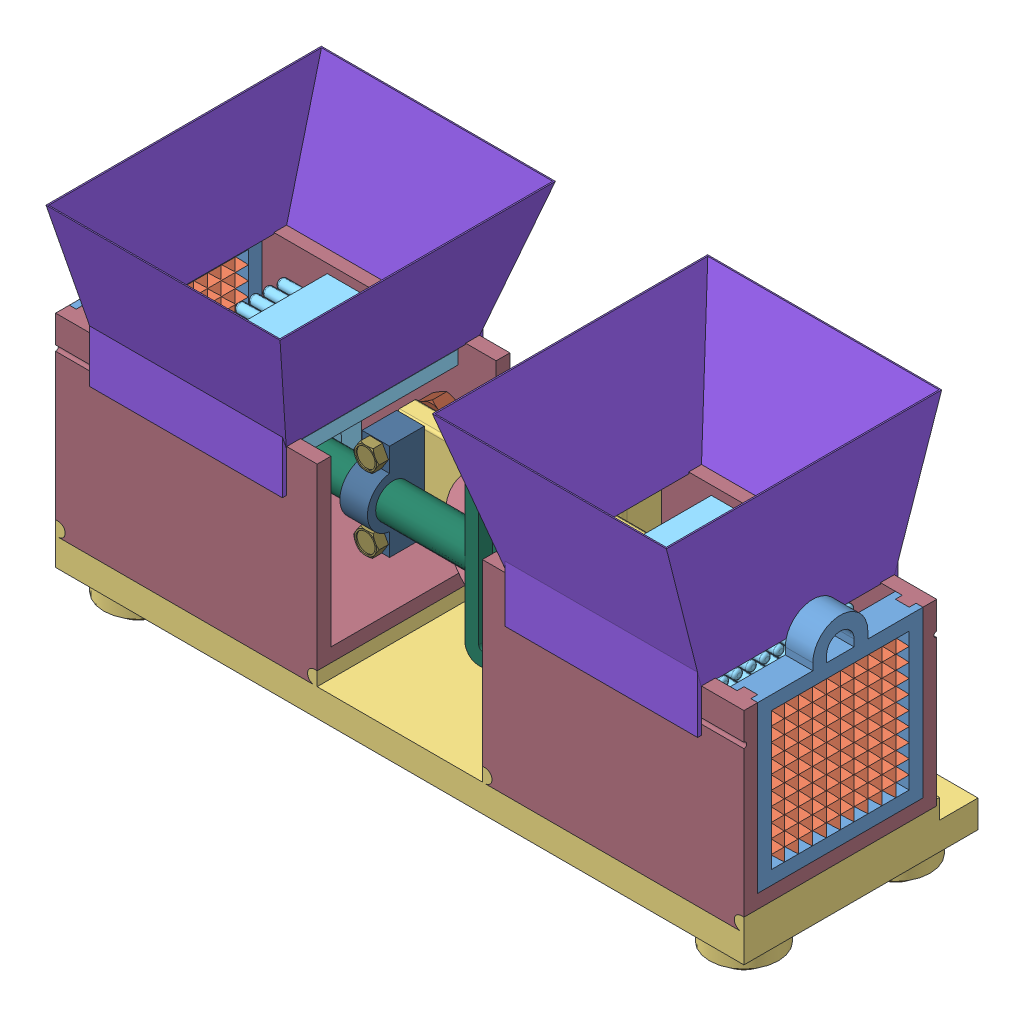
SolidWorks assembly Complete_Assmbly, configuration Default. Lengths in mm.
Overall size (546.96 281.51 365.78).
67 component instances, 15 part files, 59 mates.
Components (placement in the parent):
- Blade_assembly-1-1: Blade_assembly-1 [Default] at (92.6689 490.576 -340.9557) x (-0.150148 0.051592 0.987316) z (-0.987939 0.030407 -0.151832) size (128.96 151.07 42.39)
  - Blade Frame-1-1: Blade Frame-1 [Default] at (771.0253 -161.3106 -497.9575) x (-0.987316 0.046404 0.151832) z (-0.150148 0.037854 -0.987939) size (120 145 20)
  - Blade Piece-1-1: Blade Piece-1 [Default] at (675.3634 -97.277 -480.9651) x (0.051592 0.998205 0.030407) z (-0.150148 0.037854 -0.987939) size (1 100 20)
  - Blade Piece-1-2: Blade Piece-1 [Default] at (674.8423 -107.3589 -481.2722) x (0.051592 0.998205 0.030407) z (-0.150148 0.037854 -0.987939) size (1 100 20)
  - Blade Piece-1-3: Blade Piece-1 [Default] at (676.9266 -67.0314 -480.0438) x (0.051592 0.998205 0.030407) z (-0.150148 0.037854 -0.987939) size (1 100 20)
  - Blade Piece-1-4: Blade Piece-1 [Default] at (674.3212 -117.4408 -481.5793) x (0.051592 0.998205 0.030407) z (-0.150148 0.037854 -0.987939) size (1 100 20)
  - Blade Piece-1-5: Blade Piece-1 [Default] at (691.2502 -157.5612 -485.6895) x (0.987316 -0.046404 -0.151832) z (0.150148 -0.037854 0.987939) size (1 100 20)
  - Blade Piece-1-6: Blade Piece-1 [Default] at (681.2783 -157.0925 -484.156) x (0.987316 -0.046404 -0.151832) z (0.150148 -0.037854 0.987939) size (1 100 20)
  - Blade Piece-1-7: Blade Piece-1 [Default] at (761.0534 -160.8419 -496.424) x (0.987316 -0.046404 -0.151832) z (0.150148 -0.037854 0.987939) size (1 100 20)
  - Blade Piece-1-8: Blade Piece-1 [Default] at (676.4055 -77.1133 -480.3509) x (0.051592 0.998205 0.030407) z (-0.150148 0.037854 -0.987939) size (1 100 20)
  - Blade Piece-1-9: Blade Piece-1 [Default] at (751.0815 -160.3733 -494.8905) x (0.987316 -0.046404 -0.151832) z (0.150148 -0.037854 0.987939) size (1 100 20)
  - Blade Piece-1-10: Blade Piece-1 [Default] at (741.1096 -159.9046 -493.357) x (0.987316 -0.046404 -0.151832) z (0.150148 -0.037854 0.987939) size (1 100 20)
  - Blade Piece-1-11: Blade Piece-1 [Default] at (675.8845 -87.1952 -480.658) x (0.051592 0.998205 0.030407) z (-0.150148 0.037854 -0.987939) size (1 100 20)
  - Blade Piece-1-12: Blade Piece-1 [Default] at (701.2221 -158.0299 -487.223) x (0.987316 -0.046404 -0.151832) z (0.150148 -0.037854 0.987939) size (1 100 20)
  - Blade Piece-1-13: Blade Piece-1 [Default] at (672.758 -147.6864 -482.5007) x (0.051592 0.998205 0.030407) z (-0.150148 0.037854 -0.987939) size (1 100 20)
  - Blade Piece-1-14: Blade Piece-1 [Default] at (673.2791 -137.6045 -482.1935) x (0.051592 0.998205 0.030407) z (-0.150148 0.037854 -0.987939) size (1 100 20)
  - Blade Piece-1-15: Blade Piece-1 [Default] at (731.1377 -159.4359 -491.8235) x (0.987316 -0.046404 -0.151832) z (0.150148 -0.037854 0.987939) size (1 100 20)
  - Blade Piece-1-16: Blade Piece-1 [Default] at (721.1658 -158.9672 -490.29) x (0.987316 -0.046404 -0.151832) z (0.150148 -0.037854 0.987939) size (1 100 20)
  - Blade Piece-1-17: Blade Piece-1 [Default] at (711.1939 -158.4986 -488.7565) x (0.987316 -0.046404 -0.151832) z (0.150148 -0.037854 0.987939) size (1 100 20)
  - Blade Piece-1-18: Blade Piece-1 [Default] at (673.8002 -127.5226 -481.8864) x (0.051592 0.998205 0.030407) z (-0.150148 0.037854 -0.987939) size (1 100 20)
- Blade_assembly-2-1: Blade_assembly-2 [Default] at (352.8229 490.576 1247.7187) x (0.150148 0.051592 -0.987316) z (0.987939 0.030407 0.151832) size (128.96 151.07 42.39)
  - Blade Frame-1-1: Blade Frame-1 [Default] at (771.0253 -161.3106 -497.9575) x (-0.987316 0.046404 0.151832) z (-0.150148 0.037854 -0.987939) size (120 145 20)
  - Blade Piece-1-1: Blade Piece-1 [Default] at (675.8845 -87.1952 -480.658) x (0.051592 0.998205 0.030407) z (-0.150148 0.037854 -0.987939) size (1 100 20)
  - Blade Piece-1-2: Blade Piece-1 [Default] at (674.8423 -107.3589 -481.2722) x (0.051592 0.998205 0.030407) z (-0.150148 0.037854 -0.987939) size (1 100 20)
  - Blade Piece-1-3: Blade Piece-1 [Default] at (674.3212 -117.4408 -481.5793) x (0.051592 0.998205 0.030407) z (-0.150148 0.037854 -0.987939) size (1 100 20)
  - Blade Piece-1-4: Blade Piece-1 [Default] at (731.1377 -159.4359 -491.8235) x (0.987316 -0.046404 -0.151832) z (0.150148 -0.037854 0.987939) size (1 100 20)
  - Blade Piece-1-5: Blade Piece-1 [Default] at (676.4055 -77.1133 -480.3509) x (0.051592 0.998205 0.030407) z (-0.150148 0.037854 -0.987939) size (1 100 20)
  - Blade Piece-1-6: Blade Piece-1 [Default] at (672.758 -147.6864 -482.5007) x (0.051592 0.998205 0.030407) z (-0.150148 0.037854 -0.987939) size (1 100 20)
  - Blade Piece-1-7: Blade Piece-1 [Default] at (691.2502 -157.5612 -485.6895) x (0.987316 -0.046404 -0.151832) z (0.150148 -0.037854 0.987939) size (1 100 20)
  - Blade Piece-1-8: Blade Piece-1 [Default] at (711.1939 -158.4986 -488.7565) x (0.987316 -0.046404 -0.151832) z (0.150148 -0.037854 0.987939) size (1 100 20)
  - Blade Piece-1-9: Blade Piece-1 [Default] at (701.2221 -158.0299 -487.223) x (0.987316 -0.046404 -0.151832) z (0.150148 -0.037854 0.987939) size (1 100 20)
  - Blade Piece-1-10: Blade Piece-1 [Default] at (721.1658 -158.9672 -490.29) x (0.987316 -0.046404 -0.151832) z (0.150148 -0.037854 0.987939) size (1 100 20)
  - Blade Piece-1-11: Blade Piece-1 [Default] at (673.2791 -137.6045 -482.1935) x (0.051592 0.998205 0.030407) z (-0.150148 0.037854 -0.987939) size (1 100 20)
  - Blade Piece-1-12: Blade Piece-1 [Default] at (761.0534 -160.8419 -496.424) x (0.987316 -0.046404 -0.151832) z (0.150148 -0.037854 0.987939) size (1 100 20)
  - Blade Piece-1-13: Blade Piece-1 [Default] at (741.1096 -159.9046 -493.357) x (0.987316 -0.046404 -0.151832) z (0.150148 -0.037854 0.987939) size (1 100 20)
  - Blade Piece-1-14: Blade Piece-1 [Default] at (673.8002 -127.5226 -481.8864) x (0.051592 0.998205 0.030407) z (-0.150148 0.037854 -0.987939) size (1 100 20)
  - Blade Piece-1-15: Blade Piece-1 [Default] at (676.9266 -67.0314 -480.0438) x (0.051592 0.998205 0.030407) z (-0.150148 0.037854 -0.987939) size (1 100 20)
  - Blade Piece-1-16: Blade Piece-1 [Default] at (675.3634 -97.277 -480.9651) x (0.051592 0.998205 0.030407) z (-0.150148 0.037854 -0.987939) size (1 100 20)
  - Blade Piece-1-17: Blade Piece-1 [Default] at (751.0815 -160.3733 -494.8905) x (0.987316 -0.046404 -0.151832) z (0.150148 -0.037854 0.987939) size (1 100 20)
  - Blade Piece-1-18: Blade Piece-1 [Default] at (681.2783 -157.0925 -484.156) x (0.987316 -0.046404 -0.151832) z (0.150148 -0.037854 0.987939) size (1 100 20)
- Base-1-1: Base-1 [Default] at (222.7459 304.1921 423.0946) size (500 145 170)
- Plate-1-1: Plate-1 [Default] at (222.7459 394.1921 440.5946) x (0.696654 -0.717407 0) z (0 0 1) size (100 100 25)
- plunger slot-1-1: plunger slot-1 [Default] at (389.554 398.6957 453.3815) x (0 0 -1) z (1 0 0) size (119 119 115)
- plunger slot-1-2: plunger slot-1 [Default] at (65.554 398.6957 453.3815) x (0 0 1) z (-1 0 0) size (119 119 115)
- radial ball bearing 9100k_tfm(TOR - 9106K - 16,DE,AC,16)-1: radial ball bearing 9100k_tfm(TOR - 9106K - 16,DE,AC,16) [Default] at (222.7459 394.1921 396.8815) x (0 0 -1) z (-0.794366 0.607439 0) size (13 55 55)
- radial ball bearing 9100k_tfm(TOR - 9106K - 16,DE,AC,16)-2: radial ball bearing 9100k_tfm(TOR - 9106K - 16,DE,AC,16) [Default] at (222.7459 394.1921 424.0946) x (0 0 -1) z (0.98121 -0.192944 0) size (13 55 55)
- Hand Peddle and Shaft-1-1: Hand Peddle and Shaft-1 [Default] at (222.7459 394.1921 440.5946) x (-0.998022 -0.06286 0) z (0 0 -1) size (30 30 100)
- Hopper-1-1: Hopper-1 [Default] at (48.7249 463.1921 454.2723) x (1 0 0) z (0 1 0) size (170.04 200 130)
- Hopper-1-2: Hopper-1 [Default] at (393.4459 463.1921 452.4906) x (-1 0 0) z (0 1 0) size (170.04 200 130)
- Rubber_Feet-1-1: Rubber_Feet-1 [Default] at (442.7459 299.1921 493.3815) x (-0.123656 0 0.992325) z (0.992325 0 0.123656) size (30.79 17.51 30.02)
- Rubber_Feet-1-2: Rubber_Feet-1 [Default] at (442.7459 299.1921 383.0946) x (-0.548375 0 0.836232) z (0.836232 0 0.548375) size (30.79 17.51 30.02)
- Rubber_Feet-1-3: Rubber_Feet-1 [Default] at (2.7459 299.1921 493.3815) x (-0.548375 0 0.836232) z (0.836232 0 0.548375) size (30.79 17.51 30.02)
- Rubber_Feet-1-4: Rubber_Feet-1 [Default] at (2.7459 299.1921 383.0946) x (-0.894984 0 0.446099) z (0.446099 0 0.894984) size (30.79 17.51 30.02)
- Hinge-1-1: Hinge-1 [Default] at (317.7459 399.1921 451.238) x (-1 0 0) z (0 0 -1) size (20 70 41.72)
- Hinge-1-2: Hinge-1 [Default] at (147.7459 399.1921 451.238) x (-1 0 0) z (0 0 -1) size (20 70 41.72)
- hex nut heavy_am(B18.2.4.6M - Heavy hex nut,  M12 x 1.75 --D-S)-1: hex nut heavy_am(B18.2.4.6M - Heavy hex nut,  M12 x 1.75 --D-S) [Default] at (137.7459 372.2754 415.5946) x (0.197977 0.980207 0) z (0 0 1) size (21 24.25 12.3)
- hex nut heavy_am(B18.2.4.6M - Heavy hex nut,  M12 x 1.75 --D-S)-2: hex nut heavy_am(B18.2.4.6M - Heavy hex nut,  M12 x 1.75 --D-S) [Default] at (307.7459 425.6123 415.5946) size (21 24.25 12.3)
- hex nut heavy_am(B18.2.4.6M - Heavy hex nut,  M12 x 1.75 --D-S)-3: hex nut heavy_am(B18.2.4.6M - Heavy hex nut,  M12 x 1.75 --D-S) [Default] at (137.7459 425.6123 415.5946) size (21 24.25 12.3)
- hex nut heavy_am(B18.2.4.6M - Heavy hex nut,  M12 x 1.75 --D-S)-4: hex nut heavy_am(B18.2.4.6M - Heavy hex nut,  M12 x 1.75 --D-S) [Default] at (307.7459 372.2754 415.5946) x (0.862606 -0.505877 0) z (0 0 1) size (21 24.25 12.3)
- hex screw_am(B18.6.7M - M10 x 1.5 x 50 Indented HHMS --50S)-1: hex screw_am(B18.6.7M - M10 x 1.5 x 50 Indented HHMS --50S) [Default] at (307.7459 372.2754 463.3325) x (0 0 -1) z (0.881704 0.471802 0) size (57.5 18.48 16)
- hex screw_am(B18.6.7M - M10 x 1.5 x 50 Indented HHMS --50S)-2: hex screw_am(B18.6.7M - M10 x 1.5 x 50 Indented HHMS --50S) [Default] at (307.7459 425.6123 463.3325) x (0 0 -1) z (-0.646827 -0.762637 0) size (57.5 18.48 16)
- hex screw_am(B18.6.7M - M10 x 1.5 x 50 Indented HHMS --50S)-3: hex screw_am(B18.6.7M - M10 x 1.5 x 50 Indented HHMS --50S) [Default] at (137.7459 372.2754 463.3325) x (0 0 -1) z (0.881272 0.47261 0) size (57.5 18.48 16)
- hex screw_am(B18.6.7M - M10 x 1.5 x 50 Indented HHMS --50S)-4: hex screw_am(B18.6.7M - M10 x 1.5 x 50 Indented HHMS --50S) [Default] at (137.7459 425.6123 463.3325) x (0 0 -1) z (0.881704 0.471802 0) size (57.5 18.48 16)
- Cutting Chamber Parts-1-1: Cutting Chamber Parts-1 [Default] at (-27.2541 394.1921 453.3815) x (0 0 1) z (-1 0 0) size (140 140 190)
- Cutting Chamber Parts-1-2: Cutting Chamber Parts-1 [Default] at (472.7459 394.1921 453.3815) x (0 0 -1) z (1 0 0) size (140 140 190)
- New shaft-1-2: New shaft-1 [Default] at (331.2032 354.2066 348.5946) x (0.314826 0.949149 0) z (-0.949149 0.314826 0) size (132.23 156.43 79.99)
- Plunger_shaft-1: Plunger_shaft [Default] at (227.554 398.6957 440.8815) size (344 120 25)
Mates (geometry in assembly coordinates):
- Coincident1: coincident aligned: plane of Base-1-1 through (284.7459 329.1921 523.3815) normal (0 0 1); plane of Cutting Chamber Parts-1-2 through (282.7459 464.1921 523.3815) normal (0 0 1)
- Concentric1: concentric aligned: cylinder of Base-1-1 through (470.7459 329.1921 383.3815) axis (0 0 1) radius 5; cylinder of Cutting Chamber Parts-1-2 through (470.7459 329.1921 371.1749) axis (0 0 1) radius 5
- Coincident3: coincident aligned: plane of Base-1-1 through (282.7459 324.1921 383.3815) normal (-1 0 0); plane of Cutting Chamber Parts-1-2 through (282.7459 394.1921 453.3815) normal (-1 0 0)
- Coincident4: coincident aligned: plane of Base-1-1 through (284.7459 329.1921 523.3815) normal (0 0 1); plane of Cutting Chamber Parts-1-1 through (162.7459 464.1921 523.3815) normal (0 0 1)
- Concentric2: concentric anti-aligned: cylinder of Base-1-1 through (160.7459 329.1921 383.3815) axis (0 0 1) radius 5; cylinder of Cutting Chamber Parts-1-1 through (160.7459 329.1921 535.588) axis (0 0 -1) radius 5
- Concentric3: concentric anti-aligned: cylinder of Base-1-1 through (-25.2541 329.1921 383.3815) axis (0 0 1) radius 5; cylinder of Cutting Chamber Parts-1-1 through (-25.2541 329.1921 535.588) axis (0 0 -1) radius 5
- Concentric4: concentric anti-aligned: cylinder of Hopper-1-1 through (40.3061 442.1921 523.3815) axis (1 0 0) radius 1; cylinder of Cutting Chamber Parts-1-1 through (137.7459 442.1921 523.3815) axis (-1 0 0) radius 2
- Concentric5: concentric anti-aligned: cylinder of Hopper-1-1 through (40.3061 442.1921 383.3815) axis (1 0 0) radius 1; cylinder of Cutting Chamber Parts-1-1 through (137.7459 442.1921 383.3815) axis (-1 0 0) radius 2
- Concentric6: concentric anti-aligned: cylinder of Hopper-1-2 through (401.8647 442.1921 523.3815) axis (-1 0 0) radius 1; cylinder of Cutting Chamber Parts-1-2 through (307.7459 442.1921 523.3815) axis (1 0 0) radius 2
- Concentric7: concentric anti-aligned: cylinder of Hopper-1-2 through (401.8647 442.1921 383.3815) axis (-1 0 0) radius 1; cylinder of Cutting Chamber Parts-1-2 through (307.7459 442.1921 383.3815) axis (1 0 0) radius 2
- Coincident6: coincident aligned: plane of Plate-1-1 through (222.7459 394.1921 440.5946) normal (0 0 1); plane of Hand Peddle and Shaft-1-1 through (222.7459 394.1921 440.5946) normal (0 0 1)
- Concentric9: concentric aligned: cylinder of Plate-1-1 through (222.7459 394.1921 430.5946) axis (0 0 1) radius 15; cylinder of Hand Peddle and Shaft-1-1 through (222.7459 394.1921 340.5946) axis (0 0 1) radius 15
- Concentric13: concentric anti-aligned: cylinder of Base-1-1 through (222.7459 394.1921 303.3815) axis (0 0 1) radius 27.5; cylinder of radial ball bearing 9100k_tfm(TOR - 9106K - 16,DE,AC,16)-1 through (222.7459 394.1921 417.519) axis (0 0 -1) radius 15
- Concentric15: concentric anti-aligned: cylinder of Base-1-1 through (222.7459 394.1921 303.3815) axis (0 0 1) radius 27.5; cylinder of radial ball bearing 9100k_tfm(TOR - 9106K - 16,DE,AC,16)-2 through (222.7459 394.1921 444.7321) axis (0 0 -1) radius 15
- Coincident10: coincident aligned: plane of Base-1-1 through (197.7459 434.1921 430.5946) normal (0 0 1); plane of radial ball bearing 9100k_tfm(TOR - 9106K - 16,DE,AC,16)-2 through (226.4842 413.203 430.5946) normal (0 0 1)
- Distance1: distance = 27.2132 mm aligned: plane of radial ball bearing 9100k_tfm(TOR - 9106K - 16,DE,AC,16)-2 through (225.833 409.8915 417.5946) normal (0 0 -1); plane of radial ball bearing 9100k_tfm(TOR - 9106K - 16,DE,AC,16)-1 through (213.0269 381.4822 390.3815) normal (0 0 -1)
- Concentric17: concentric anti-aligned: cylinder of radial ball bearing 9100k_tfm(TOR - 9106K - 16,DE,AC,16)-1 through (222.7459 394.1921 417.519) axis (0 0 -1) radius 15; cylinder of Hand Peddle and Shaft-1-1 through (222.7459 394.1921 340.5946) axis (0 0 1) radius 15
- Coincident12: coincident anti-aligned: plane of Base-1-1 through (197.7459 434.1921 430.5946) normal (0 0 1); plane of Plate-1-1 through (222.7459 394.1921 430.5946) normal (0 0 -1)
- Coincident15: coincident anti-aligned: plane of Base-1-1 through (197.7459 434.1921 430.5946) normal (0 0 1); plane of Hinge-1-2 through (127.7459 371.6921 430.5946) normal (0 0 -1)
- Width2: width aligned: plane of Base-1-1 through (222.7459 434.1921 423.0946) normal (0 1 0); plane of Base-1-1 through (127.7459 364.1921 316.5997) normal (0 -1 0); plane of Hinge-1-2 through (127.7459 434.1921 430.5946) normal (0 1 0); plane of Hinge-1-2 through (127.7459 364.1921 430.5946) normal (0 -1 0)
- Coincident16: coincident aligned: plane of Base-1-1 through (127.7459 434.1921 316.5997) normal (-1 0 0); plane of Hinge-1-2 through (127.7459 398.6957 453.3815) normal (-1 0 0)
- Width3: width aligned: plane of Base-1-1 through (127.7459 434.1921 316.5997) normal (-1 0 0); plane of Base-1-1 through (317.7459 434.1921 316.5997) normal (1 0 0); plane of Hinge-1-2 through (127.7459 398.6957 453.3815) normal (-1 0 0); plane of Hinge-1-1 through (317.7459 398.6957 453.3815) normal (1 0 0)
- Coincident17: coincident anti-aligned: plane of Base-1-1 through (197.7459 434.1921 430.5946) normal (0 0 1); plane of Hinge-1-1 through (297.7459 371.6921 430.5946) normal (0 0 -1)
- Width5: width aligned: plane of Base-1-1 through (222.7459 434.1921 423.0946) normal (0 1 0); plane of Base-1-1 through (317.7459 364.1921 316.5997) normal (0 -1 0); plane of Hinge-1-1 through (297.7459 434.1921 430.5946) normal (0 1 0); plane of Hinge-1-1 through (297.7459 364.1921 430.5946) normal (0 -1 0)
- Lock3: lock: unknown of Plate-1-1; unknown of Hand Peddle and Shaft-1-1
- Coincident20: coincident aligned: plane of Blade_assembly-2-1/Blade Frame-1-1 through (-7.2541 464.1921 403.3815) normal (0 1 0); plane of Cutting Chamber Parts-1-1 through (162.7459 464.1921 383.3815) normal (0 1 0)
- Coincident21: coincident anti-aligned: plane of Blade_assembly-2-1/Blade Frame-1-1 through (-17.2541 354.1921 508.3815) normal (0 0 1); plane of Cutting Chamber Parts-1-1 through (-22.2541 344.1921 508.3815) normal (0 0 -1)
- Coincident22: coincident aligned: plane of Blade_assembly-2-1/Blade Frame-1-1 through (-27.2541 354.1921 403.3815) normal (-1 0 0); plane of Cutting Chamber Parts-1-1 through (-27.2541 394.1921 453.3815) normal (-1 0 0)
- Coincident23: coincident aligned: plane of Blade_assembly-1-1/Blade Frame-1-1 through (472.7459 354.1921 503.3815) normal (1 0 0); plane of Cutting Chamber Parts-1-2 through (472.7459 394.1921 453.3815) normal (1 0 0)
- Coincident24: coincident aligned: plane of Blade_assembly-1-1/Blade Frame-1-1 through (452.7459 464.1921 503.3815) normal (0 1 0); plane of Cutting Chamber Parts-1-2 through (282.7459 464.1921 523.3815) normal (0 1 0)
- Coincident25: coincident anti-aligned: plane of Blade_assembly-1-1/Blade Frame-1-1 through (462.7459 354.1921 398.3815) normal (0 0 -1); plane of Cutting Chamber Parts-1-2 through (467.7459 344.1921 398.3815) normal (0 0 1)
- Parallel7: parallel aligned: plane of Blade_assembly-1-1/Blade Frame-1-1 through (452.7459 354.1921 513.3815) normal (0 0 1); plane of plunger slot-1-1 through (414.554 458.1957 512.8815) normal (0 0 1)
- Parallel8: parallel aligned: plane of Blade_assembly-2-1/Blade Frame-1-1 through (-7.2541 354.1921 513.3815) normal (0 0 1); plane of plunger slot-1-2 through (40.554 458.1957 512.8815) normal (0 0 1)
- Concentric26: concentric aligned: cylinder of Hand Peddle and Shaft-1-1 through (222.7459 394.1921 340.5946) axis (0 0 1) radius 15; cylinder of New shaft-1-2 through (222.7459 394.1921 338.5946) axis (0 0 1) radius 15
- Coincident30: coincident aligned: circle of Hand Peddle and Shaft-1-1; circle of New shaft-1-2
- Lock4: lock: unknown of Hand Peddle and Shaft-1-1; unknown of New shaft-1-2
- Concentric27: concentric aligned: cylinder of Hinge-1-2 through (127.7459 398.6957 453.3815) axis (1 0 0) radius 12.5; cylinder of Plunger_shaft-1 through (52.554 398.6957 453.3815) axis (1 0 0) radius 12.5
- Concentric28: concentric anti-aligned: cylinder of Hinge-1-1 through (297.7459 398.6957 453.3815) axis (1 0 0) radius 12.5; cylinder of Plunger_shaft-1 through (402.554 398.6957 453.3815) axis (-1 0 0) radius 12.5
- Parallel9: parallel anti-aligned: plane of Plate-1-1 through (222.7459 394.1921 440.5946) normal (0 0 1); plane of Plunger_shaft-1 through (227.554 398.6957 440.8815) normal (0 0 -1)
- Tangent1: tangent anti-aligned: cylinder of Plate-1-1 through (227.554 433.9021 455.5946) axis (0 0 -1) radius 5; plane of Plunger_shaft-1 through (222.554 348.6957 465.8815) normal (1 0 0)
- Coincident34: coincident anti-aligned: plane of plunger slot-1-1 through (399.554 398.6957 453.3815) normal (-1 0 0); plane of Plunger_shaft-1 through (399.554 398.6957 453.3815) normal (1 0 0)
- Coincident35: coincident anti-aligned: plane of plunger slot-1-2 through (55.554 398.6957 453.3815) normal (1 0 0); plane of Plunger_shaft-1 through (55.554 398.6957 453.3815) normal (-1 0 0)
- Concentric29: concentric aligned: cylinder of plunger slot-1-2 through (55.554 398.6957 453.3815) axis (1 0 0) radius 12.5; cylinder of Plunger_shaft-1 through (52.554 398.6957 453.3815) axis (1 0 0) radius 12.5
- Coincident36: coincident anti-aligned: plane of Hinge-1-1 through (297.7459 434.1921 455.8325) normal (0 0 1); plane of hex screw_am(B18.6.7M - M10 x 1.5 x 50 Indented HHMS --50S)-2 through (311.5591 422.3782 455.8325) normal (0 0 -1)
- Coincident37: coincident anti-aligned: plane of Base-1-1 through (197.7459 434.1921 415.5946) normal (0 0 -1); plane of hex nut heavy_am(B18.2.4.6M - Heavy hex nut,  M12 x 1.75 --D-S)-2 through (286.7459 425.6123 415.5946) normal (0 0 1)
- Concentric30: concentric anti-aligned: circle of Hinge-1-1; circle of hex nut heavy_am(B18.2.4.6M - Heavy hex nut,  M12 x 1.75 --D-S)-2
- Coincident40: coincident anti-aligned: plane of Base-1-1 through (197.7459 434.1921 415.5946) normal (0 0 -1); plane of hex nut heavy_am(B18.2.4.6M - Heavy hex nut,  M12 x 1.75 --D-S)-4 through (289.6312 382.8989 415.5946) normal (0 0 1)
- Concentric31: concentric anti-aligned: circle of Hinge-1-1; circle of hex nut heavy_am(B18.2.4.6M - Heavy hex nut,  M12 x 1.75 --D-S)-4
- Coincident41: coincident anti-aligned: plane of Base-1-1 through (197.7459 434.1921 415.5946) normal (0 0 -1); plane of hex nut heavy_am(B18.2.4.6M - Heavy hex nut,  M12 x 1.75 --D-S)-1 through (133.5884 351.6911 415.5946) normal (0 0 1)
- Concentric32: concentric aligned: circle of Hinge-1-2; circle of hex nut heavy_am(B18.2.4.6M - Heavy hex nut,  M12 x 1.75 --D-S)-1
- Coincident44: coincident anti-aligned: plane of Base-1-1 through (197.7459 434.1921 415.5946) normal (0 0 -1); plane of hex nut heavy_am(B18.2.4.6M - Heavy hex nut,  M12 x 1.75 --D-S)-3 through (116.7459 425.6123 415.5946) normal (0 0 1)
- Concentric34: concentric aligned: circle of Hinge-1-2; circle of hex nut heavy_am(B18.2.4.6M - Heavy hex nut,  M12 x 1.75 --D-S)-3
- Coincident45: coincident anti-aligned: plane of Hinge-1-2 through (127.7459 371.6921 455.8325) normal (0 0 1); plane of hex screw_am(B18.6.7M - M10 x 1.5 x 50 Indented HHMS --50S)-3 through (135.3828 376.6818 455.8325) normal (0 0 -1)
- Coincident46: coincident anti-aligned: plane of Hinge-1-2 through (127.7459 434.1921 455.8325) normal (0 0 1); plane of hex screw_am(B18.6.7M - M10 x 1.5 x 50 Indented HHMS --50S)-4 through (135.3869 430.0209 455.8325) normal (0 0 -1)
- Coincident47: coincident anti-aligned: plane of Hinge-1-1 through (297.7459 371.6921 455.8325) normal (0 0 1); plane of hex screw_am(B18.6.7M - M10 x 1.5 x 50 Indented HHMS --50S)-1 through (305.3869 376.684 455.8325) normal (0 0 -1)
- Concentric35: concentric aligned: cone of hex nut heavy_am(B18.2.4.6M - Heavy hex nut,  M12 x 1.75 --D-S)-3 through (137.7459 425.6123 403.32) axis (0 0 1); cylinder of hex screw_am(B18.6.7M - M10 x 1.5 x 50 Indented HHMS --50S)-4 through (137.7459 425.6123 488.7325) axis (0 0 1) radius 5
- Concentric36: concentric aligned: cone of hex nut heavy_am(B18.2.4.6M - Heavy hex nut,  M12 x 1.75 --D-S)-1 through (137.7459 372.2754 403.32) axis (0 0 1); cylinder of hex screw_am(B18.6.7M - M10 x 1.5 x 50 Indented HHMS --50S)-3 through (137.7459 372.2754 488.7325) axis (0 0 1) radius 5
- Concentric37: concentric aligned: cone of hex nut heavy_am(B18.2.4.6M - Heavy hex nut,  M12 x 1.75 --D-S)-4 through (307.7459 372.2754 403.32) axis (0 0 1); cylinder of hex screw_am(B18.6.7M - M10 x 1.5 x 50 Indented HHMS --50S)-1 through (307.7459 372.2754 488.7325) axis (0 0 1) radius 5
- Concentric38: concentric aligned: cone of hex nut heavy_am(B18.2.4.6M - Heavy hex nut,  M12 x 1.75 --D-S)-2 through (307.7459 425.6123 403.32) axis (0 0 1); cylinder of hex screw_am(B18.6.7M - M10 x 1.5 x 50 Indented HHMS --50S)-2 through (307.7459 425.6123 488.7325) axis (0 0 1) radius 5
